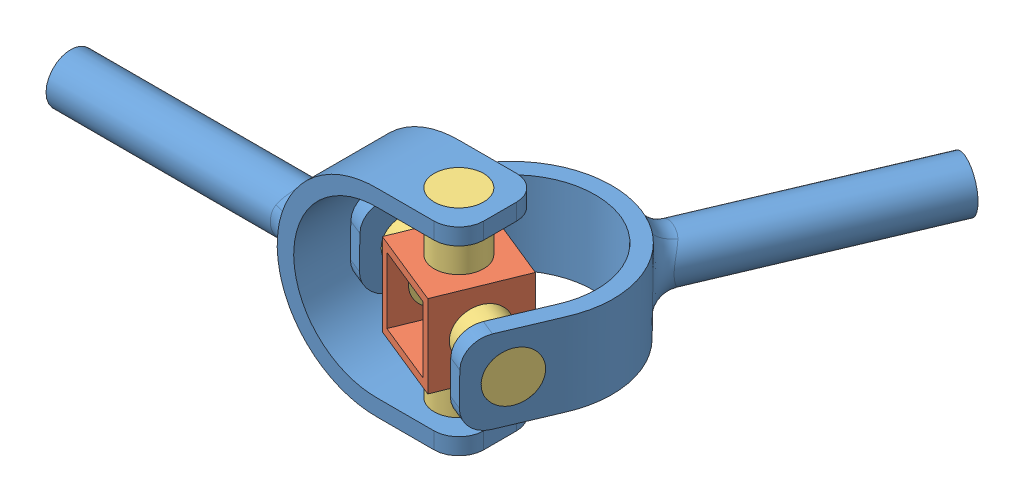
SolidWorks assembly Yucra_Fabrizio_E02, configuration Predeterminado. Lengths in mm.
Overall size (379.92 121.69 287.19).
7 component instances, 3 part files, 12 mates.
Components (placement in the parent):
- Yucra_Fabrizio_P54A-1: Yucra_Fabrizio_P54A [Predeterminado] at (57.602 16.6659 235.0001) x (0 1 0) z (0 0 -1) size (121.69 260 50)
- Yucra_Fabrizio_P54B-1: Yucra_Fabrizio_P54B [Predeterminado] at (23.1929 16.6659 283.1619) x (0.926471 0 0.376365) z (-0.376365 0 0.926471) size (50 50 50)
- Yucra_Fabrizio_P54C-1: Yucra_Fabrizio_P54C [Predeterminado] at (32.602 36.6659 260.0001) size (30 40 30)
- Yucra_Fabrizio_P54C-2: Yucra_Fabrizio_P54C [Predeterminado] at (-22.9863 16.6659 237.4182) x (-0.195933 0.853805 0.482315) z (0.321342 0.520594 -0.791025) size (30 40 30)
- Yucra_Fabrizio_P54C-3: Yucra_Fabrizio_P54C [Predeterminado] at (32.602 -43.3341 260.0001) size (30 40 30)
- Yucra_Fabrizio_P54C-4: Yucra_Fabrizio_P54C [Predeterminado] at (51.1314 16.6659 267.5274) x (0.139509 0.928762 -0.34342) z (0.349554 -0.370676 -0.860472) size (30 40 30)
- Yucra_Fabrizio_P54A-2: Yucra_Fabrizio_P54A [Predeterminado] at (23.3 41.9473 282.8982) x (-0.926471 0 -0.376365) z (0.00426 0.999936 -0.010487) size (121.69 260 50)
Mates (geometry in assembly coordinates):
- Concéntrica1: concentric anti-aligned: cylinder of Yucra_Fabrizio_P54A-1 through (32.602 -43.3341 260.0001) axis (0 1 0) radius 15; cylinder of Yucra_Fabrizio_P54C-1 through (32.602 76.6659 260.0001) axis (0 -1 0) radius 15
- Tangente1: tangent: plane of assembly; face of Yucra_Fabrizio_P54A-1; plane of Yucra_Fabrizio_P54C-1 through (32.602 76.6659 260.0001) normal (0 1 0)
- Concéntrica2: concentric anti-aligned: cylinder of Yucra_Fabrizio_P54A-1 through (32.602 -43.3341 260.0001) axis (0 1 0) radius 15; cylinder of Yucra_Fabrizio_P54C-3 through (32.602 -3.3341 260.0001) axis (0 -1 0) radius 15
- Tangente2: tangent: plane of assembly; face of Yucra_Fabrizio_P54A-1; plane of Yucra_Fabrizio_P54C-3 through (32.602 -43.3341 260.0001) normal (0 -1 0)
- Concéntrica3: concentric anti-aligned: cylinder of Yucra_Fabrizio_P54B-1 through (32.602 -50.7605 260.0001) axis (0 1 0) radius 15; cylinder of Yucra_Fabrizio_P54C-1 through (32.602 76.6659 260.0001) axis (0 -1 0) radius 15
- Coincidente1: coincident aligned: plane of Yucra_Fabrizio_P54B-1 through (23.4817 36.6659 229.311) normal (0 -1 0); plane of Yucra_Fabrizio_P54C-1 through (32.602 36.6659 260.0001) normal (0 -1 0)
- Concéntrica4: concentric anti-aligned: cylinder of Yucra_Fabrizio_P54B-1 through (-29.8666 16.6659 234.6231) axis (0.926471 0 0.376365) radius 15; cylinder of Yucra_Fabrizio_P54C-4 through (88.1903 16.6659 282.582) axis (-0.926471 0 -0.376365) radius 15
- Coincidente7: coincident aligned: plane of Yucra_Fabrizio_P54B-1 through (60.5406 -3.3341 244.3656) normal (-0.926471 0 -0.376365); plane of Yucra_Fabrizio_P54C-4 through (51.1314 16.6659 267.5274) normal (-0.926471 0 -0.376365)
- Concéntrica5: concentric anti-aligned: cylinder of Yucra_Fabrizio_P54B-1 through (-29.8666 16.6659 234.6231) axis (0.926471 0 0.376365) radius 15; cylinder of Yucra_Fabrizio_P54C-2 through (14.0726 16.6659 252.4728) axis (-0.926471 0 -0.376365) radius 15
- Coincidente8: coincident aligned: plane of Yucra_Fabrizio_P54B-1 through (23.4817 -3.3341 229.311) normal (0.926471 0 0.376365); plane of Yucra_Fabrizio_P54C-2 through (14.0726 16.6659 252.4728) normal (0.926471 0 0.376365)
- Concéntrica7: concentric aligned: cylinder of Yucra_Fabrizio_P54A-2 through (88.1903 16.6659 282.582) axis (-0.926471 0 -0.376365) radius 15; cylinder of Yucra_Fabrizio_P54C-2 through (14.0726 16.6659 252.4728) axis (-0.926471 0 -0.376365) radius 15
- Coincidente9: coincident aligned: plane of Yucra_Fabrizio_P54C-2 through (-22.9863 16.6659 237.4182) normal (-0.926471 0 -0.376365); circle of Yucra_Fabrizio_P54A-2
